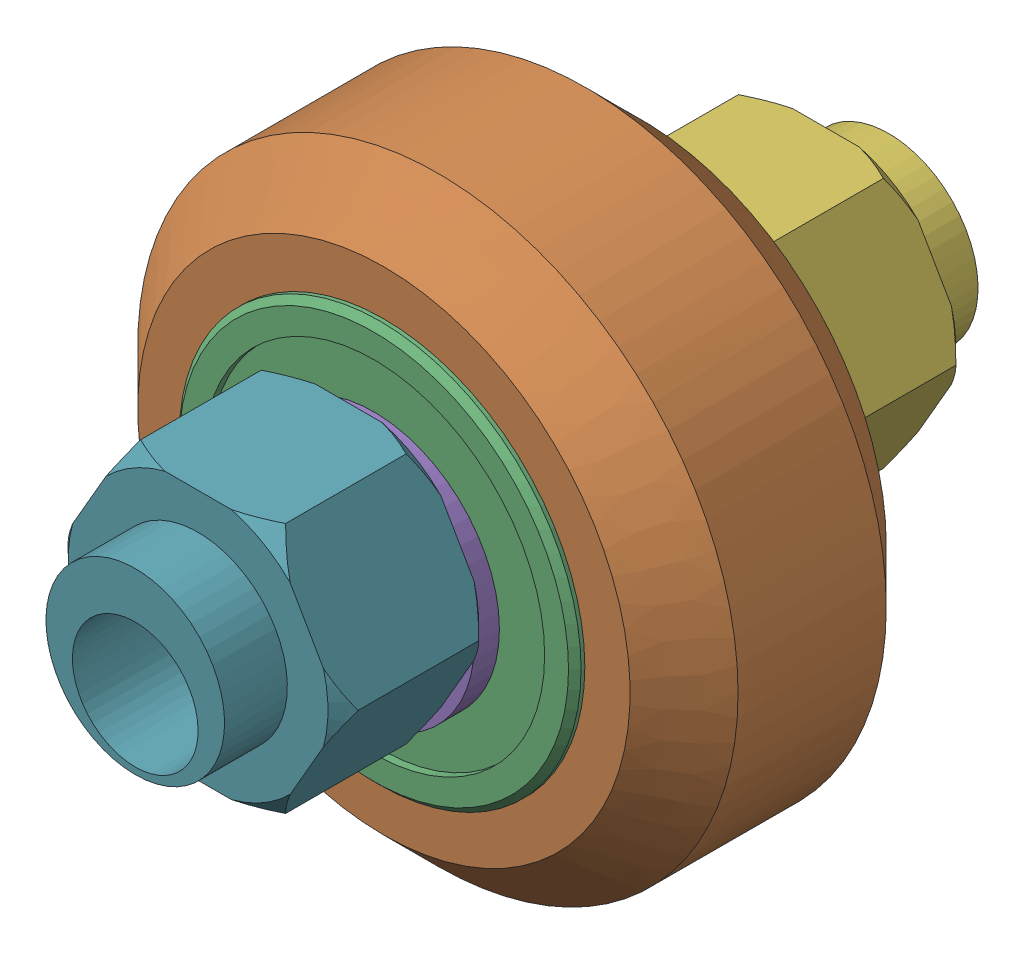
SolidWorks assembly Outboard Wheel Stack_3, configuration Default. Lengths in mm.
Overall size (23.9 23.9 30).
9 component instances, 4 part files, 0 mates.
Components (placement in the parent):
- Xtreme Solid V Wheel Kit Assembly_7-1: Xtreme Solid V Wheel Kit Assembly_7 [Default] at origin size (23.9 23.9 13)
  - Precision Shim - 10x5x1mm-1: Precision Shim - 10x5x1mm [Default] at origin size (10 10 1)
  - Xtreme Solid V Wheel Assembly_7-1: Xtreme Solid V Wheel Assembly_7 [Default] at (115.15 25.79 -23.5) size (23.9 23.9 11)
    - Xtreme Solid V Wheel-1: Xtreme Solid V Wheel [Default] at (-115.15 -25.79 30) x (0 0 1) z (-1 0 0) size (10.2 23.9 23.9)
    - Wheel+Kit+-+5x16x5mm+Sealed+Radial+Ball+Bearing.step.f3d-1: Wheel+Kit+-+5x16x5mm+Sealed+Radial+Ball+Bearing.step.f3d [Default] at (-115.15 -25.79 30) x (0 1 0) z (-1 0 0) size (16 5 16)
    - Wheel+Kit+-+5x16x5mm+Sealed+Radial+Ball+Bearing.step.f3d-2: Wheel+Kit+-+5x16x5mm+Sealed+Radial+Ball+Bearing.step.f3d [Default] at (-115.15 -25.79 30) x (0 1 0) z (1 0 0) size (16 5 16)
  - Precision Shim - 10x5x1mm-2: Precision Shim - 10x5x1mm [Default] at (0 0 12) size (10 10 1)
- Eccentric Spacer 6mm-1: Eccentric Spacer 6mm [Default] at (0 0.79 -6) x (1 0 0) z (0 -1 0) size (11.55 8.5 10)
- Eccentric Spacer 6mm-2: Eccentric Spacer 6mm [Default] at (0 0.79 19) x (-1 0 0) z (0 -1 0) size (11.55 8.5 10)
